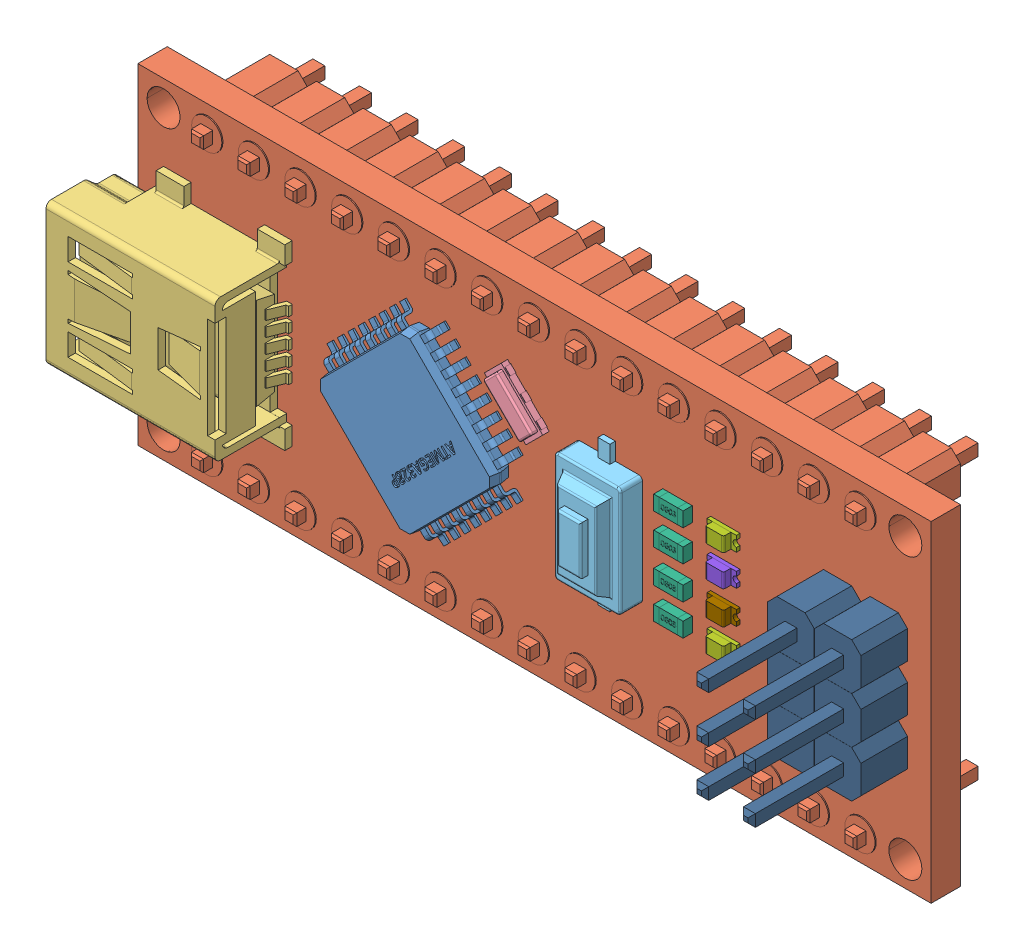
SolidWorks assembly Arduino Nano.STEP, configuration Default. Lengths in mm.
Overall size (44.28 18 13.68).
28 component instances, 14 part files, 0 mates.
Components (placement in the parent):
- ATMEGA328P-AU.STEP.STEP-1: ATMEGA328P-AU.STEP.STEP [Default] at (19.8219 24.4243 4.0882) x (-0.707107 -0.707107 0) z (0 0 1) size (9 9 1.2)
  - ATMEGA328P-AU--3DModel-STEP-56544.step.STEP.STEP.STEP.STEP-1: ATMEGA328P-AU--3DModel-STEP-56544.step.STEP.STEP.STEP.STEP [Default] at (2.8163 4.1 0.6768) x (1 0 0) z (0 -1 0) size (9 1.2 9)
- Arduino Nano.STEP-1: Arduino Nano.STEP [Default] at (8.8551 11.9484 0) size (43.18 18 6.8)
- Mini USB.STEP-1: Mini USB.STEP [Default] at (8.5451 19.5727 4.14) size (9.5 9.7 3.9)
- CSTCE Crystal.STEP-1: CSTCE Crystal.STEP [Default] at (25.8562 23.1047 4.15) x (0.707107 -0.707107 0) z (0 0 1) size (3.2 1.35 0.71)
- 2Pin Tactile Switch 6x3.6.STEP-1: 2Pin Tactile Switch 6x3.6.STEP [Default] at (30.7142 19.8184 4.14) x (0 1 0) z (0 0 1) size (7.9 3.6 2.2)
- 0603 Resistor.STEP-1: 0603 Resistor.STEP [Default] at (34.4251 22.4184 4.14) size (1.6 0.8 0.5)
- 0603 Resistor.STEP-2: 0603 Resistor.STEP [Default] at (34.4251 20.7184 4.14) size (1.6 0.8 0.5)
- 0603 Resistor.STEP-3: 0603 Resistor.STEP [Default] at (34.4251 18.9184 4.14) size (1.6 0.8 0.5)
- 0603 Resistor.STEP-4: 0603 Resistor.STEP [Default] at (34.4251 17.2184 4.14) size (1.6 0.8 0.5)
- Blue LED.STEP-1: Blue LED.STEP [Default] at (37.0251 22.4184 4.14) size (1.6 0.8 0.6)
- Green LED.STEP-1: Green LED.STEP [Default] at (37.0251 20.7184 4.14) size (1.6 0.8 0.6)
- Red LED.STEP-1: Red LED.STEP [Default] at (37.0251 18.9184 4.14) size (1.6 0.8 0.6)
- Blue LED.STEP-2: Blue LED.STEP [Default] at (37.0251 17.2184 4.14) size (1.6 0.8 0.6)
- Header 2x3.STEP-1: Header 2x3.STEP [Default] at (45.6765 17.0321 4.14) x (0 1 0) z (0 0 1) size (7.62 5.07 10)
- SOT89.STEP-1: SOT89.STEP [Default] at (38.4751 17.3184 0.94) x (0 1 0) z (0 0 1) size (6.5 7.1 1.6)
- 1206 Tantalum.STEP-1: 1206 Tantalum.STEP [Default] at (38.6251 22.3684 2.54) x (-1 0 0) z (0 0 -1) size (3.2 1.6 1.5)
- 0603 Resistor.STEP-5: 0603 Resistor.STEP [Default] at (38.4251 24.9684 2.54) x (-1 0 0) z (0 0 -1) size (1.6 0.8 0.5)
- 0603 Capacitor.STEP-1: 0603 Capacitor.STEP [Default] at (35.0338 14.4684 2.54) x (-1 0 0) z (0 0 -1) size (1.6 0.8 0.7)
- 1206 Tantalum.STEP-2: 1206 Tantalum.STEP [Default] at (7.6451 24.3684 2.54) x (1 0 0) z (0 0 -1) size (3.2 1.6 1.5)
- 0603 Capacitor.STEP-2: 0603 Capacitor.STEP [Default] at (6.9059 22.4745 2.54) x (-1 0 0) z (0 0 -1) size (1.6 0.8 0.7)
- 0603 Capacitor.STEP-3: 0603 Capacitor.STEP [Default] at (17.8451 14.0245 2.54) x (-1 0 0) z (0 0 -1) size (1.6 0.8 0.7)
- 0603 Capacitor.STEP-4: 0603 Capacitor.STEP [Default] at (17.8451 15.0767 2.54) x (-1 0 0) z (0 0 -1) size (1.6 0.8 0.7)
- 0603 Capacitor.STEP-5: 0603 Capacitor.STEP [Default] at (25.3451 21.2855 2.54) x (-1 0 0) z (0 0 -1) size (1.6 0.8 0.7)
- 0603 Resistor.STEP-6: 0603 Resistor.STEP [Default] at (23.8451 15.8601 2.54) x (-1 0 0) z (0 0 -1) size (1.6 0.8 0.5)
- 0603 Resistor.STEP-7: 0603 Resistor.STEP [Default] at (23.8451 14.4709 2.54) x (-1 0 0) z (0 0 -1) size (1.6 0.8 0.5)
- CSTCE Crystal.STEP-2: CSTCE Crystal.STEP [Default] at (13.1731 14.7184 2.53) x (-1 0 0) z (0 0 -1) size (3.2 1.35 0.71)
- SOIC16.STEP-1: SOIC16.STEP [Default] at (16.6451 19.5642 2.54) x (-1 0 0) z (0 0 -1) size (10.2 6 1.5)
